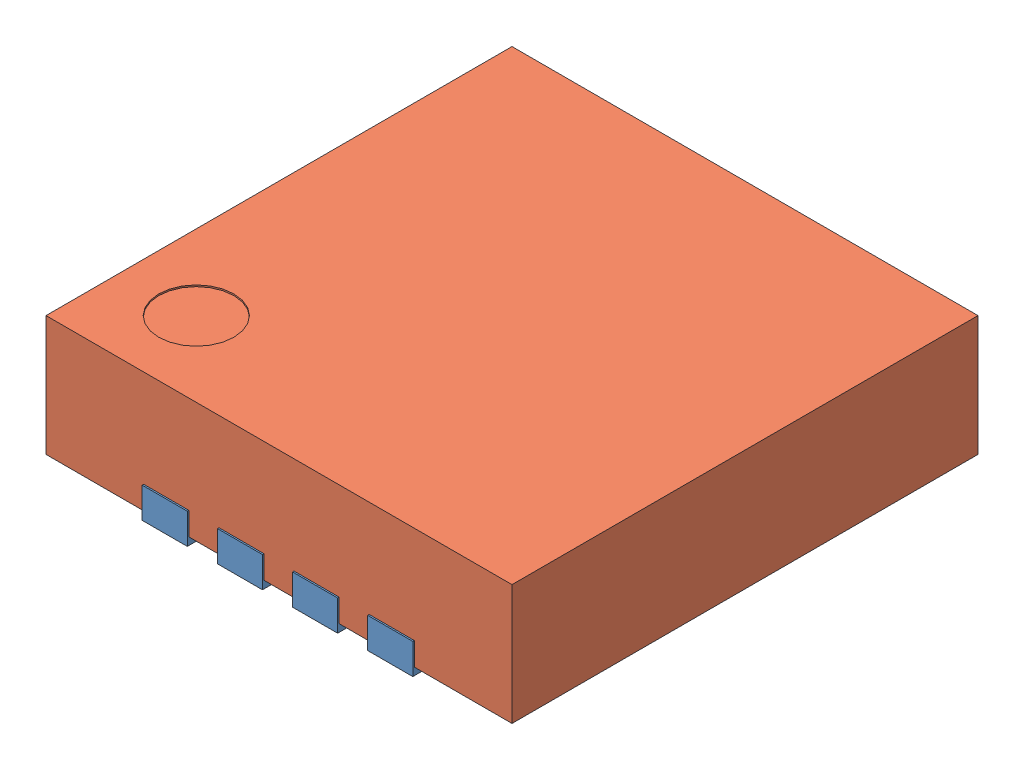
SolidWorks assembly CP-8-13, configuration Default. Lengths in mm.
Overall size (3.1 0.85 3.12).
10 component instances, 3 part files, 9 mates.
Components (placement in the parent):
- P-17: P [Default] at (-0.75 0 1.385) size (0.3 0.2 0.5)
- P-18: P [Default] at (-0.25 0 1.385) size (0.3 0.2 0.5)
- P-19: P [Default] at (0.25 0 1.385) size (0.3 0.2 0.5)
- P-20: P [Default] at (0.75 0 1.385) size (0.3 0.2 0.5)
- P-21: P [Default] at (-0.75 0 -1.385) x (-1 0 0) z (0 0 -1) size (0.3 0.2 0.5)
- P-22: P [Default] at (-0.25 0 -1.385) x (-1 0 0) z (0 0 -1) size (0.3 0.2 0.5)
- P-23: P [Default] at (0.25 0 -1.385) x (-1 0 0) z (0 0 -1) size (0.3 0.2 0.5)
- P-24: P [Default] at (0.75 0 -1.385) x (-1 0 0) z (0 0 -1) size (0.3 0.2 0.5)
- Body-2: Body [Default] at (0 0.05 0) size (3.1 0.8 3.1)
- EP-3: EP [Default] at (0 0.203 0) x (-1 0 0) z (0 0 1) size (1.84 0.2 1.55)
Mates (geometry in assembly coordinates):
- Coincident11: coincident: plane of P-17 through (-0.75 0 1.21) normal (0 -1 0); plane of assembly through (0 0 0) normal (0 1 0)
- Distance5: distance = 0.75 mm: plane of P-17 through (-0.75 0 1.385) normal (1 0 0); plane of assembly through (0 0 0) normal (1 0 0)
- Distance6: distance = 1.56 mm: plane of P-17 through (-0.9 0.203 1.56) normal (0 0 1); plane of assembly through (0 0 0) normal (0 0 1)
- Coincident14: coincident: plane of Body-2 through (0 0.05 0) normal (0 0 1); plane of assembly
- Coincident15: coincident: plane of Body-2 through (0 0.05 0) normal (1 0 0); plane of assembly
- Distance7: distance = 0.05 mm: plane of Body-2 through (0 0.05 0) normal (0 -1 0); plane of P-17 through (-0.75 0 1.21) normal (0 -1 0)
- Coincident17: coincident: plane of EP-3 through (0 0.203 0) normal (0 0 1); plane of assembly
- Coincident18: coincident: plane of EP-3 through (0 0.203 0) normal (-1 0 0); plane of assembly
- Coincident19: coincident: plane of P-20 through (0.75 0 1.21) normal (0 -1 0); plane of EP-3 through (0 0 0) normal (0 -1 0)
